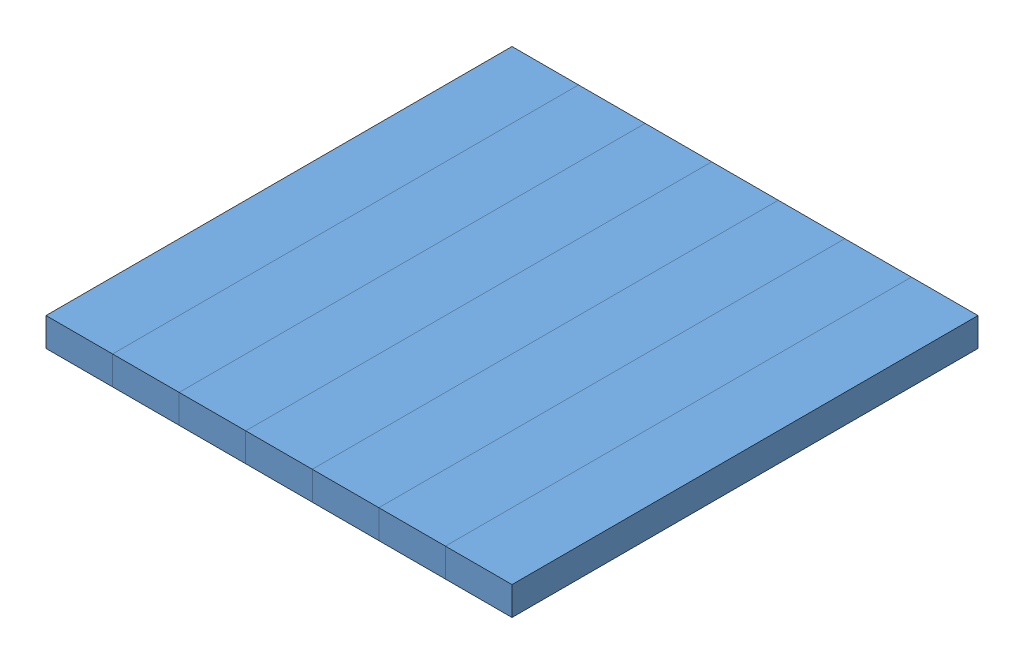
SolidWorks assembly short_side, configuration Default. Lengths in mm.
Overall size (622.3 38.1 622.3).
7 component instances, 1 part files, 18 mates.
Components (placement in the parent):
- 24in_2x4-1: 24in_2x4 [Default] at (-374.5222 371.3202 -54.6392) size (88.9 38.1 622.3)
- 24in_2x4-2: 24in_2x4 [Default] at (-285.6222 371.3202 -54.6392) size (88.9 38.1 622.3)
- 24in_2x4-3: 24in_2x4 [Default] at (-196.7222 371.3202 -54.6392) size (88.9 38.1 622.3)
- 24in_2x4-4: 24in_2x4 [Default] at (-107.8222 371.3202 -54.6392) size (88.9 38.1 622.3)
- 24in_2x4-5: 24in_2x4 [Default] at (69.9778 371.3202 -54.6392) size (88.9 38.1 622.3)
- 24in_2x4-6: 24in_2x4 [Default] at (158.8778 371.3202 -54.6392) size (88.9 38.1 622.3)
- 24in_2x4-8: 24in_2x4 [Default] at (-18.9222 371.3202 -54.6392) size (88.9 38.1 622.3)
Mates (geometry in assembly coordinates):
- Coincident1: coincident anti-aligned: plane of 24in_2x4-1 through (-330.0722 390.3702 567.6608) normal (1 0 0); plane of 24in_2x4-2 through (-330.0722 390.3702 567.6608) normal (-1 0 0)
- Coincident2: coincident anti-aligned: plane of 24in_2x4-2 through (-241.1722 390.3702 567.6608) normal (1 0 0); plane of 24in_2x4-3 through (-241.1722 390.3702 567.6608) normal (-1 0 0)
- Coincident3: coincident anti-aligned: plane of 24in_2x4-3 through (-152.2722 390.3702 567.6608) normal (1 0 0); plane of 24in_2x4-4 through (-152.2722 390.3702 567.6608) normal (-1 0 0)
- Coincident6: coincident anti-aligned: plane of 24in_2x4-5 through (114.4278 390.3702 567.6608) normal (1 0 0); plane of 24in_2x4-6 through (114.4278 390.3702 567.6608) normal (-1 0 0)
- Coincident7: coincident aligned: plane of 24in_2x4-1 through (-330.0722 352.2702 567.6608) normal (0 0 1); plane of 24in_2x4-2 through (-241.1722 352.2702 567.6608) normal (0 0 1)
- Coincident8: coincident aligned: plane of 24in_2x4-2 through (-241.1722 352.2702 567.6608) normal (0 0 1); plane of 24in_2x4-3 through (-152.2722 352.2702 567.6608) normal (0 0 1)
- Coincident9: coincident aligned: plane of 24in_2x4-3 through (-152.2722 352.2702 567.6608) normal (0 0 1); plane of 24in_2x4-4 through (-63.3722 352.2702 567.6608) normal (0 0 1)
- Coincident12: coincident aligned: plane of 24in_2x4-5 through (114.4278 352.2702 567.6608) normal (0 0 1); plane of 24in_2x4-6 through (203.3278 352.2702 567.6608) normal (0 0 1)
- Coincident13: coincident aligned: plane of 24in_2x4-1 through (-418.9722 390.3702 567.6608) normal (0 1 0); plane of 24in_2x4-2 through (-330.0722 390.3702 567.6608) normal (0 1 0)
- Coincident14: coincident aligned: plane of 24in_2x4-2 through (-330.0722 390.3702 567.6608) normal (0 1 0); plane of 24in_2x4-3 through (-241.1722 390.3702 567.6608) normal (0 1 0)
- Coincident15: coincident aligned: plane of 24in_2x4-3 through (-241.1722 390.3702 567.6608) normal (0 1 0); plane of 24in_2x4-4 through (-152.2722 390.3702 567.6608) normal (0 1 0)
- Coincident18: coincident aligned: plane of 24in_2x4-5 through (25.5278 390.3702 567.6608) normal (0 1 0); plane of 24in_2x4-6 through (114.4278 390.3702 567.6608) normal (0 1 0)
- Coincident19: coincident anti-aligned: plane of 24in_2x4-4 through (-63.3722 390.3702 567.6608) normal (1 0 0); plane of 24in_2x4-8 through (-63.3722 390.3702 567.6608) normal (-1 0 0)
- Coincident20: coincident anti-aligned: plane of 24in_2x4-5 through (25.5278 390.3702 567.6608) normal (-1 0 0); plane of 24in_2x4-8 through (25.5278 390.3702 567.6608) normal (1 0 0)
- Coincident21: coincident aligned: plane of 24in_2x4-4 through (-63.3722 352.2702 567.6608) normal (0 0 1); plane of 24in_2x4-8 through (25.5278 352.2702 567.6608) normal (0 0 1)
- Coincident22: coincident aligned: plane of 24in_2x4-5 through (114.4278 352.2702 567.6608) normal (0 0 1); plane of 24in_2x4-8 through (25.5278 352.2702 567.6608) normal (0 0 1)
- Coincident23: coincident aligned: plane of 24in_2x4-4 through (-152.2722 390.3702 567.6608) normal (0 1 0); plane of 24in_2x4-8 through (-63.3722 390.3702 567.6608) normal (0 1 0)
- Coincident24: coincident aligned: plane of 24in_2x4-5 through (25.5278 390.3702 567.6608) normal (0 1 0); plane of 24in_2x4-8 through (-63.3722 390.3702 567.6608) normal (0 1 0)
